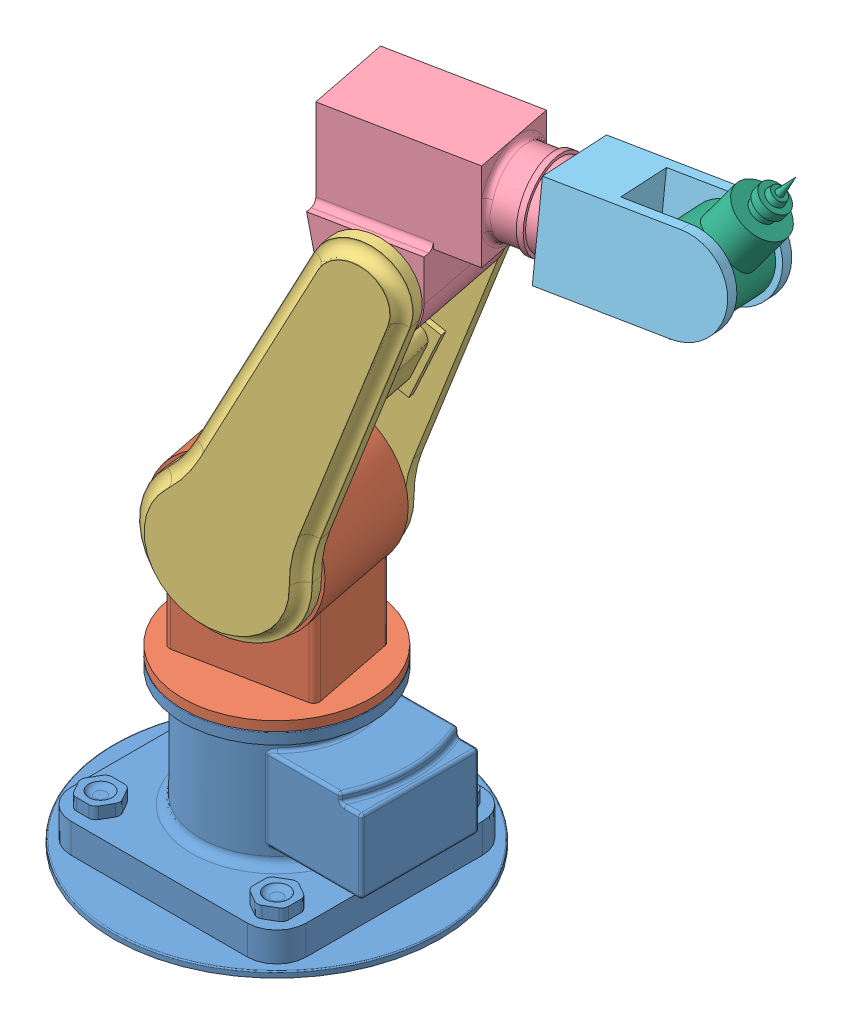
SolidWorks assembly Assem1, configuration Default. Lengths in mm.
Overall size (1110.02 1375.92 555).
6 component instances, 6 part files, 10 mates.
Components (placement in the parent):
- Part1 Base-1: Part1 Base [Default] at (157.687 81.8201 498.1883) size (555 280 555)
- Part2 Link-1: Part2 Link [Default] at (157.687 241.8201 498.1883) x (0.980903 0 -0.194499) z (0.194499 0 0.980903) size (320 466 320)
- Part3 Link2-1: Part3 Link2 [Default] at (157.687 577.8201 498.1883) x (0.902554 -0.391621 -0.178964) z (-0.384143 -0.920126 0.07617) size (250 260.14 700)
- part4 LINK 3 1-1: part4 LINK 3 1 [Default] at (258.9808 1182.8833 478.1032) x (0.980903 0 -0.194499) z (0.194499 0 0.980903) size (639.46 297.5 180)
- part4 LINK 3 2-1: part4 LINK 3 2 [Default] at (258.9808 1182.8833 478.1032) x (0.980903 0 -0.194499) z (0.192379 0.147252 0.97021) size (518.46 150 140)
- Part5 Link4-1: Part5 Link4 [Default] at (769.0502 1182.8833 376.9636) x (0.540254 0.809466 -0.22998) z (0.192379 0.147252 0.97021) size (372.99 130 100)
Mates (geometry in assembly coordinates):
- Concentric1: concentric anti-aligned: cylinder of Part1 Base-1 through (157.687 161.8201 498.1883) axis (0 1 0) radius 100; cylinder of Part2 Link-1 through (157.687 361.8201 498.1883) axis (0 -1 0) radius 100
- Coincident1: coincident anti-aligned: plane of Part1 Base-1 through (157.687 361.8201 498.1883) normal (0 1 0); plane of Part2 Link-1 through (157.687 361.8201 498.1883) normal (0 -1 0)
- Concentric2: concentric aligned: cylinder of Part2 Link-1 through (175.1919 577.8201 586.4696) axis (-0.194499 0 -0.980903) radius 75; cylinder of Part3 Link2-1 through (175.1919 577.8201 586.4696) axis (-0.194499 0 -0.980903) radius 75
- Coincident2: coincident anti-aligned: plane of Part2 Link-1 through (140.182 577.8201 409.9071) normal (-0.194499 0 -0.980903); plane of Part3 Link2-1 through (-77.1685 815.5661 453.0046) normal (0.194499 0 0.980903)
- Concentric3: concentric aligned: cylinder of Part3 Link2-1 through (367.2631 1037.8833 548.3845) axis (-0.194499 0 -0.980903) radius 50; cylinder of part4 LINK 3 1-1 through (367.2631 1037.8833 548.3845) axis (-0.194499 0 -0.980903) radius 50
- Coincident3: coincident anti-aligned: plane of Part3 Link2-1 through (-42.1586 815.5661 629.5671) normal (-0.194499 0 -0.980903); plane of part4 LINK 3 1-1 through (367.2631 1037.8833 548.3845) normal (0.194499 0 0.980903)
- Coincident4: coincident anti-aligned: plane of part4 LINK 3 1-1 through (572.8697 1182.8833 415.8635) normal (0.980903 0 -0.194499); plane of part4 LINK 3 2-1 through (584.1881 1267.3734 472.9452) normal (-0.980903 0 0.194499)
- Coincident5: coincident: line of part4 LINK 3 1-1 through (572.8697 1182.8833 415.8635) axis (0.980903 0 -0.194499); point of part4 LINK 3 2-1
- Concentric4: concentric aligned: cylinder of part4 LINK 3 2-1 through (778.6691 1190.2459 425.4741) axis (-0.192379 -0.147252 -0.97021) radius 50; cylinder of Part5 Link4-1 through (778.6691 1190.2459 425.4741) axis (-0.192379 -0.147252 -0.97021) radius 50
- Coincident6: coincident anti-aligned: plane of part4 LINK 3 2-1 through (759.4312 1175.5208 328.4531) normal (0.192379 0.147252 0.97021); plane of Part5 Link4-1 through (759.4312 1175.5208 328.4531) normal (-0.192379 -0.147252 -0.97021)
